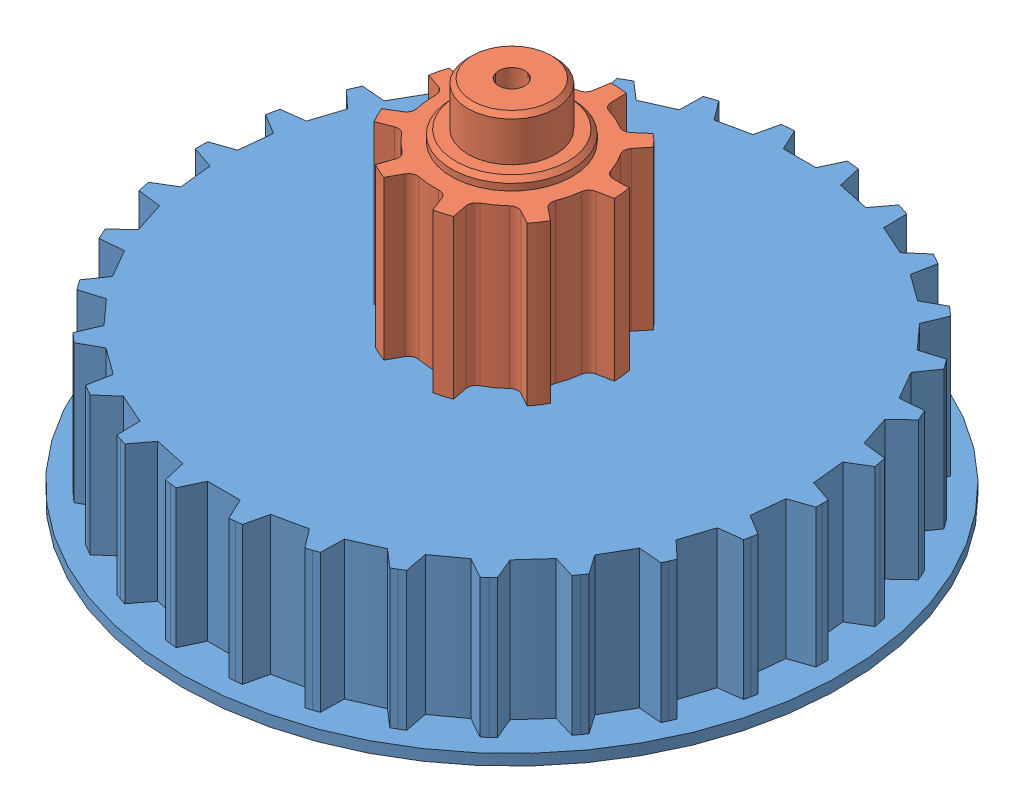
SolidWorks assembly centre pulley, configuration Default. Lengths in mm.
Overall size (30 19 30).
2 component instances, 2 part files, 3 mates.
Components (placement in the parent):
- transmission pulley centre-1: transmission pulley centre [Default] at (7.726 11.8465 25.1899) size (30 6.8 30)
- centre pulley-1: centre pulley [Default] at (7.726 25.3465 25.1899) x (0.694658 0 -0.71934) z (0 -1 0) size (8.98 9.1 19)
Mates (geometry in assembly coordinates):
- Concentric1: concentric aligned: circle of transmission pulley centre-1; cylinder of centre pulley-1 through (7.726 27.8465 25.1899) axis (0 -1 0) radius 1.995
- Distance1: distance = 0 mm aligned: plane of transmission pulley centre-1 through (7.726 11.3465 25.1899) normal (0 -1 0); plane of centre pulley-1 through (7.726 11.3465 25.1899) normal (0 -1 0)
- Coincident3: coincident anti-aligned: plane of transmission pulley centre-1 through (5.824 8.1465 21.819) normal (-0.75471 0 0.656059); plane of centre pulley-1 through (8.3117 11.3465 24.6808) normal (0.75471 0 -0.656059)
